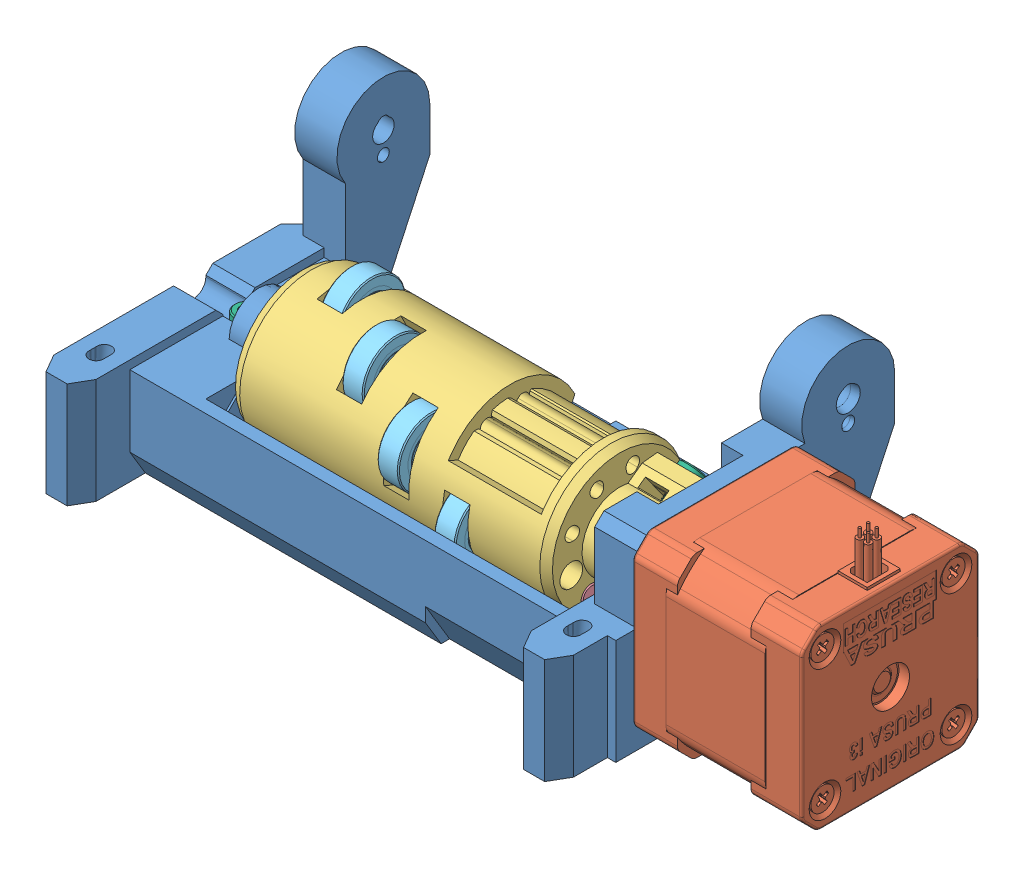
SolidWorks assembly MMU2 Idler Assembly, configuration Default. Lengths in mm.
Overall size (165 58.02 78.33).
19 component instances, 6 part files, 8 mates.
Components (placement in the parent):
- mmu2-idler-body(M1)-1: mmu2-idler-body(M1) [Default] at (74.386 71.0234 92.8254) x (-1 0 0) z (0 -1 0) size (125 78.33 58.02)
- NEMA-17 40mm PR-1: NEMA-17 40mm PR [По умолчанию] at (143.386 71.0234 92.8254) x (0 0 -1) z (0 1 0) size (42.3 62 51.35)
- MMU2 Idler Shaft Assembly-1: MMU2 Idler Shaft Assembly [Default] at (81.8402 44.4461 182.585) x (-1 0 0) z (0 -0.405266 -0.914199) size (95 39.64 31.09)
  - mmu2-idler(M1)-1: mmu2-idler(M1) [Default] at (7.4542 60.6735 71.2872) size (95 34 28)
  - 5x16 Shaft-1: 5x16 Shaft [Default] at (66.4542 72.4912 69.2035) x (0 0 -1) z (1 0 0) size (5 5 16)
  - 625 Bearing-1: 625 Bearing [6153K15] at (66.4542 72.4912 69.2035) x (0 0 -1) z (1 0 0) size (16 16 5)
  - 625 Bearing-2: 625 Bearing [6153K15] at (52.4542 68.3869 62.0947) x (0 0 -1) z (1 0 0) size (16 16 5)
  - 625 Bearing-3: 625 Bearing [6153K15] at (38.4542 60.6735 59.2872) x (0 0 -1) z (1 0 0) size (16 16 5)
  - 625 Bearing-4: 625 Bearing [6153K15] at (24.4542 52.96 62.0947) x (0 0 -1) z (1 0 0) size (16 16 5)
  - 625 Bearing-5: 625 Bearing [6153K15] at (10.4542 48.8558 69.2035) x (0 0 -1) z (1 0 0) size (16 16 5)
  - 625 Bearing-6: 625 Bearing [6153K15] at (74.9542 60.6735 71.2872) x (0 0 -1) z (1 0 0) size (16 16 5)
  - 5x16 Shaft-2: 5x16 Shaft [Default] at (52.4542 68.3869 62.0947) x (0 0 -1) z (1 0 0) size (5 5 16)
  - 5x16 Shaft-3: 5x16 Shaft [Default] at (38.4542 60.6735 59.2872) x (0 0 -1) z (1 0 0) size (5 5 16)
  - 5x16 Shaft-4: 5x16 Shaft [Default] at (24.4542 52.96 62.0947) x (0 0 -1) z (1 0 0) size (5 5 16)
  - 5x16 Shaft-5: 5x16 Shaft [Default] at (10.4542 48.8558 69.2035) x (0 0 -1) z (1 0 0) size (5 5 16)
  - M3-10 Screw-1: M3-10 Screw [93235A313] at (-12.5458 62.726 72.4723) x (0.999493 -0.015924 0.027582) z (0 -0.866025 -0.5) size (5.5 5.5 13.21)
  - M3-10 Screw-2: M3-10 Screw [93235A313] at (-2.5458 62.726 72.4723) x (0.596164 -0.401431 0.6953) z (0 -0.866025 -0.5) size (5.5 5.5 13.21)
- 5x16 Shaft-1: 5x16 Shaft [Default] at (1.886 71.0234 92.8254) x (0 0.20462 -0.978842) z (1 0 0) size (5 5 16)
- M3-10 Screw-1: M3-10 Screw [93235A313] at (-9.114 59.0234 92.8254) x (0.999809 0 0.019535) z (0 -1 0) size (5.5 5.5 13.21)
Mates (geometry in assembly coordinates):
- Concentric1: concentric anti-aligned: cylinder of mmu2-idler-body(M1)-1 through (104.386 71.0234 92.8254) axis (-1 0 0) radius 11.5; cylinder of NEMA-17 40mm PR-1 through (101.386 71.0234 92.8254) axis (1 0 0) radius 11
- Coincident1: coincident anti-aligned: plane of mmu2-idler-body(M1)-1 through (103.386 95.0234 71.8254) normal (1 0 0); plane of NEMA-17 40mm PR-1 through (103.386 71.0234 92.8254) normal (-1 0 0)
- Concentric2: concentric aligned: cylinder of NEMA-17 40mm PR-1 through (81.386 71.0234 92.8254) axis (1 0 0) radius 2.5; circle of MMU2 Idler Shaft Assembly-1/mmu2-idler(M1)-1
- Coincident2: coincident anti-aligned: plane of mmu2-idler-body(M1)-1 through (15.386 71.0234 92.8254) normal (1 0 0); plane of MMU2 Idler Shaft Assembly-1/625 Bearing-1 through (15.386 82.6716 89.9411) normal (-1 0 0)
- Concentric3: concentric aligned: cylinder of mmu2-idler-body(M1)-1 through (4.386 71.0234 92.8254) axis (-1 0 0) radius 2.55; cylinder of 5x16 Shaft-1 through (9.886 71.0234 92.8254) axis (-1 0 0) radius 2.5
- Coincident3: coincident aligned: plane of mmu2-idler-body(M1)-1 through (-6.114 71.0234 92.8254) normal (-1 0 0); plane of 5x16 Shaft-1 through (-6.114 71.0234 92.8254) normal (-1 0 0)
- Concentric4: concentric aligned: cone of mmu2-idler-body(M1)-1 through (-9.114 68.0234 92.8254) axis (0 -1 0); cylinder of M3-10 Screw-1 through (-9.114 72.0234 92.8254) axis (0 -1 0) radius 2.75
- Coincident4: coincident anti-aligned: plane of mmu2-idler-body(M1)-1 through (-9.114 59.0234 92.8254) normal (0 1 0); plane of M3-10 Screw-1 through (-9.114 59.0234 92.8254) normal (0 -1 0)
